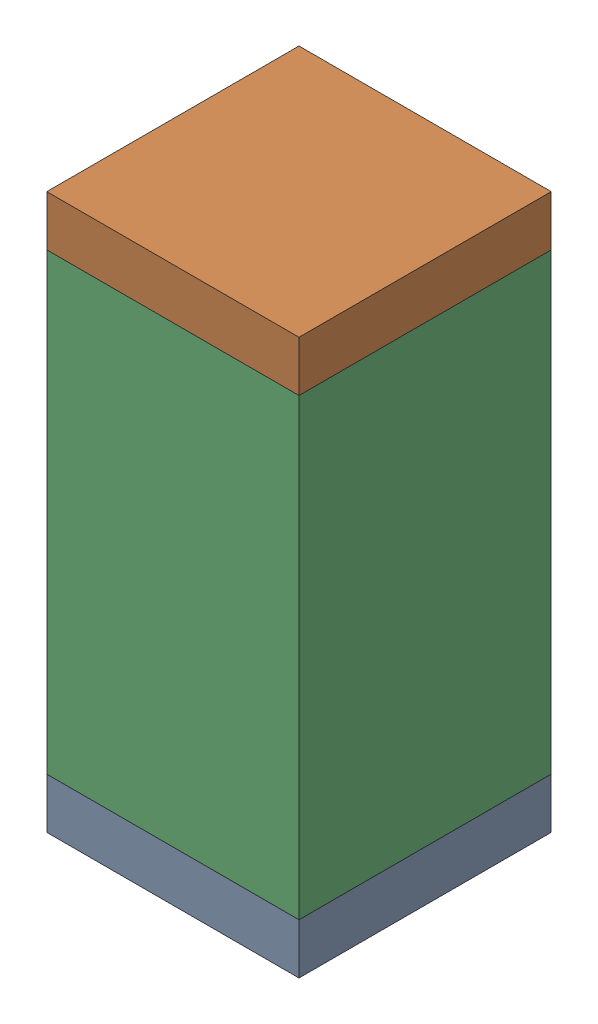
SolidWorks assembly C110, configuration Default. Lengths in mm.
Overall size (0.5 1.1 0.5).
6 component instances, 2 part files, 0 mates.
Components (placement in the parent):
- 810157360-1: 810157360 [Default] at (115.75 79 0) size (0.5 0.1 0.5)
  - Extruded_9-1: Extruded_9 [Default] at origin size (0.5 0.1 0.5)
- 810157360-2: 810157360 [Default] at (115.75 80 0) size (0.5 0.1 0.5)
  - Extruded_9-1: Extruded_9 [Default] at origin size (0.5 0.1 0.5)
- 791586336-1: 791586336 [Default] at (115.75 79.5 0) size (0.5 0.9 0.5)
  - Extruded_8-1: Extruded_8 [Default] at origin size (0.5 0.9 0.5)
